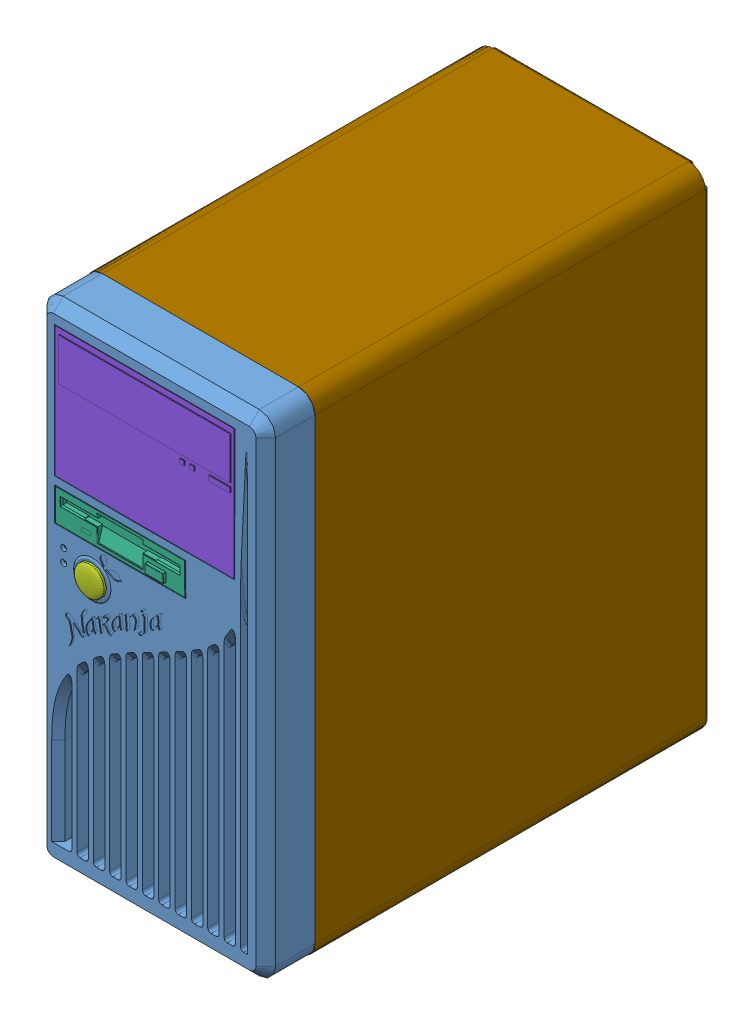
SolidWorks assembly Exercise 19, configuration Default. Lengths in mm.
Overall size (177.8 381 349.22).
10 component instances, 10 part files, 33 mates.
Components (placement in the parent):
- PC Front bezel-1: PC Front bezel [Default] at origin size (177.8 381 39.34)
- Cover-1: Cover [Default] at origin size (177.8 381 314.05) (hidden)
- Skeleton-1: Skeleton [Default] at origin size (168.5 365.05 3.17)
- Back Bezel-1: Back Bezel [Default] at origin size (173.74 376.94 25.4)
- Frame-1: Frame [Default] at origin size (23.23 86.39 299.08)
- Fan_Comair_Muffin-XL-1: Fan_Comair_Muffin-XL [Default] at (-30.4641 43.5386 -271.3666) size (67.9 67.9 22.3)
- 3_5_floppy-1: 3_5_floppy [Standard] at (-24.3644 55.1708 34.1) size (101.2 25.4 146)
- Power Button-1: Power Button [Default] at origin size (22.87 22.87 42.9)
- Front Cap-1: Front Cap [Default] at origin size (139.19 101.09 38.86)
- Cover2-1: Cover2 [Default] at origin size (177.8 381 306.32)
Mates (geometry in assembly coordinates):
- Inplace1: in place: plane of ?; moOrthogonalPlaneRef_w of ? through (-1000 1000 1000) axis (-1 0 0); line of ? through (-1000 1000 1000) axis (-1 0 0); unknown of ?
- Coincident1: coincident aligned: 
- Coincident2: coincident aligned: plane of Cover-1 through (0 0 0) normal (0 1 0)
- Coincident3: coincident anti-aligned: plane of Cover-1 through (0 0 0) normal (1 0 0)
- Inplace2: in place: line of ? through (-1000 1000 1000) axis (-1 0 0); line of ? through (-1000 1000 1000) axis (-1 0 0); line of ? through (-1000 1000 1000) axis (-1 0 0); unknown of ?
- Coincident4: coincident aligned: 
- Coincident5: coincident aligned: plane of Skeleton-1 through (0 0 0) normal (0 1 0)
- Coincident6: coincident anti-aligned: plane of Skeleton-1 through (0 0 0) normal (1 0 0)
- Inplace3: in place: line of ? through (-1000 1000 1000) axis (-1 0 0); line of ? through (-1000 1000 1000) axis (-1 0 0); line of ? through (-1000 1000 1000) axis (-1 0 0); unknown of ?
- Coincident7: coincident aligned: 
- Coincident8: coincident aligned: plane of Back Bezel-1 through (0 0 0) normal (0 1 0)
- Coincident9: coincident anti-aligned: plane of Back Bezel-1 through (0 0 0) normal (1 0 0)
- Inplace4: in place: line of ? through (-1000 1000 1000) axis (-1 0 0); line of ? through (-1000 1000 1000) axis (-1 0 0); line of ? through (-1000 1000 1000) axis (-1 0 0); unknown of ?
- Coincident10: coincident aligned: 
- Coincident11: coincident aligned: plane of Frame-1 through (0 0 0) normal (0 1 0)
- Coincident12: coincident anti-aligned: plane of Frame-1 through (0 0 0) normal (1 0 0)
- Concentric1: concentric aligned: cylinder of Back Bezel-1 through (-60.325 73.3996 -279.4) axis (0 0 -1) radius 2.54; cylinder of Fan_Comair_Muffin-XL-1 through (-60.325 73.3996 -279.9639) axis (0 0 -1) radius 1.1076
- Coincident1: coincident anti-aligned: plane of Back Bezel-1 through (76.2 -177.8 -302.26) normal (0 0 1); plane of Fan_Comair_Muffin-XL-1 through (-64.415 9.5878 -302.26) normal (0 0 -1)
- Coincident3: coincident aligned: plane of PC Front bezel-1 through (-88.9 -190.5 38.1) normal (0 0 1); plane of 3_5_floppy-1 through (-74.9644 67.7208 38.1) normal (0 0 1)
- Coincident4: coincident anti-aligned: plane of PC Front bezel-1 through (-75.1564 67.7208 0) normal (0 -1 0); plane of 3_5_floppy-1 through (-74.6644 67.7208 -105.9) normal (0 1 0)
- Distance1: distance = 0.508 mm anti-aligned: plane of PC Front bezel-1 through (26.4436 67.7208 0) normal (-1 0 0); plane of 3_5_floppy-1 through (25.9356 67.7208 -105.9) normal (1 0 0)
- Inplace5: in place: line of ? through (-1000 1000 1000) axis (-1 0 0); line of ? through (-1000 1000 1000) axis (-1 0 0); line of ? through (-1000 1000 1000) axis (-1 0 0); unknown of ?
- Coincident6: coincident aligned: 
- Coincident7: coincident aligned: plane of Power Button-1 through (0 0 0) normal (0 1 0)
- Coincident8: coincident anti-aligned: plane of Power Button-1 through (0 0 0) normal (1 0 0)
- Inplace6: in place: line of ? through (-1000 1000 1000) axis (-1 0 0); line of ? through (-1000 1000 1000) axis (-1 0 0); line of ? through (-1000 1000 1000) axis (-1 0 0); unknown of ?
- Coincident9: coincident aligned: 
- Coincident10: coincident aligned: plane of Front Cap-1 through (0 0 0) normal (0 1 0)
- Coincident11: coincident anti-aligned: plane of Front Cap-1 through (0 0 0) normal (1 0 0)
- InPlace7: in place: plane of ? through (0 0 0) normal (0 0 1); plane of ? through (0 0 0) normal (0 1 0); plane of ? through (0 0 0) normal (1 0 0); unknown of ?
- Coincident5: coincident aligned: 
- Coincident6: coincident aligned: plane of Part1^Exercise 19-1 through (0 0 0) normal (0 1 0)
- Coincident7: coincident anti-aligned: plane of Part1^Exercise 19-1 through (0 0 0) normal (1 0 0)
